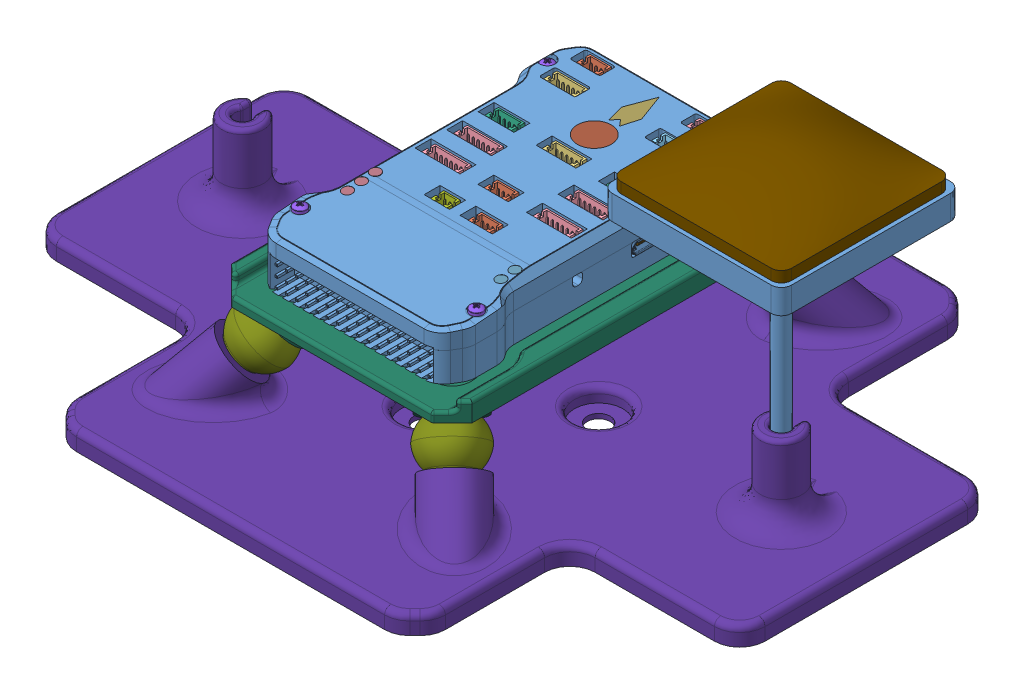
SolidWorks assembly S1000_Pixhawk, configuration Default. Lengths in mm.
Overall size (179 88.11 141.22).
35 component instances, 19 part files, 23 mates.
Components (placement in the parent):
- Pixhawk-1: Pixhawk [Défaut] at (-0.2703 0 -1.2478) x (-1 0 0) z (0 1 0) size (49.31 81.3 15.24)
  - Pixhawk APM-1: Pixhawk APM [Défaut] at (-24.9203 -39.4022 0) size (49.31 81.3 15.03)
  - DF13-3P-1.25DSA-1: DF13-3P-1.25DSA [Défaut] at (0.001 -60.127 12.2305) x (0 -1 0) z (-1 0 0) size (3.4 6.6 5.4)
  - DF13-5P-1.25DSA-1: DF13-5P-1.25DSA [Défaut] at (0.5502 -52.3839 12.2305) x (0 -1 0) z (-1 0 0) size (3.4 6.6 7.9)
  - DF13-6P-1.25DSA-1: DF13-6P-1.25DSA [Défaut] at (-27.5951 -60.0382 12.2305) x (0 -1 0) z (-1 0 0) size (3.4 6.6 9.15)
  - DF13-7P-1.25DSA-1: DF13-7P-1.25DSA [Défaut] at (-26.4213 -52.538 12.2305) x (0 -1 0) z (-1 0 0) size (3.4 6.6 10.4)
  - DF13-4P-1.25DSA-1: DF13-4P-1.25DSA [Défaut] at (-0.0265 -37.0823 12.2305) x (0 -1 0) z (-1 0 0) size (3.4 6.6 6.65)
  - DF13-4P-1.25DSA-2: DF13-4P-1.25DSA [Défaut] at (-30.3382 -37.0823 12.2305) x (0 -1 0) z (-1 0 0) size (3.4 6.6 6.65)
  - DF13-5P-1.25DSA-2: DF13-5P-1.25DSA [Défaut] at (-14.4216 -37.0823 12.2305) x (0 -1 0) z (-1 0 0) size (3.4 6.6 7.9)
  - DF13-6P-1.25DSA-2: DF13-6P-1.25DSA [Défaut] at (-0.012 -29.2904 12.2305) x (0 -1 0) z (-1 0 0) size (3.4 6.6 9.15)
  - DF13-6P-1.25DSA-3: DF13-6P-1.25DSA [Défaut] at (-0.012 -21.2194 12.2305) x (0 -1 0) z (-1 0 0) size (3.4 6.6 9.15)
  - DF13-6P-1.25DSA-4: DF13-6P-1.25DSA [Défaut] at (-27.948 -29.2904 12.2305) x (0 -1 0) z (-1 0 0) size (3.4 6.6 9.15)
  - DF13-6P-1.25DSA-5: DF13-6P-1.25DSA [Défaut] at (-27.948 -21.2194 12.2305) x (0 -1 0) z (-1 0 0) size (3.4 6.6 9.15)
  - DF13-3P-1.25DSA-2: DF13-3P-1.25DSA [Défaut] at (-15.6441 -21.2194 12.2305) x (0 -1 0) z (-1 0 0) size (3.4 6.6 5.4)
  - DF13-2P-1.25DSA-1: DF13-2P-1.25DSA [Défaut] at (-11.2684 -12.1811 12.2305) x (0 -1 0) z (-1 0 0) size (3.4 6.6 4.15)
  - DF13-3P-1.25DSA-3: DF13-3P-1.25DSA [Défaut] at (-20.7011 -12.1811 12.2305) x (0 -1 0) z (-1 0 0) size (3.4 6.6 5.4)
  - pan head cross recess screw_iso-1: pan head cross recess screw_iso [ISO 7045 - M1.6 x 3 - Z --- 3N] at (21.8797 32.2978 14.8) x (0 0 -1) z (1 0 0) size (4.27 3.2 3.2)
  - pan head cross recess screw_iso-2: pan head cross recess screw_iso [ISO 7045 - M1.6 x 3 - Z --- 3N] at (-22.4203 32.2978 14.8) x (0 0 -1) z (1 0 0) size (4.27 3.2 3.2)
  - pan head cross recess screw_iso-3: pan head cross recess screw_iso [ISO 7045 - M1.6 x 3 - Z --- 3N] at (21.8797 -29.8022 14.8) x (0 0 -1) z (1 0 0) size (4.27 3.2 3.2)
  - pan head cross recess screw_iso-4: pan head cross recess screw_iso [ISO 7045 - M1.6 x 3 - Z --- 3N] at (-22.4203 -29.8022 14.8) x (0 0 -1) z (1 0 0) size (4.27 3.2 3.2)
  - micro USB-2: micro USB [Défaut] at (-38.5288 4.0262 13.8589) x (0 1 0) z (-1 0 0) size (7.99 2.94 5.43)
    - micro usb02-1: micro usb02 [Défaut] at (-14.4796 6.4719 -20.7085) size (6.9 2.16 4.2)
    - micro USB-1: micro USB [Défaut] at (-14.4796 6.4719 -16.0085) size (7.99 2.94 5.43)
  - pièce10^Pixhawk-1: pièce10^Pixhawk [Défaut] at (-24.9203 -39.4022 14.5) size (8.5 8.5 0.5) (virtual)
  - pièce11^Pixhawk-1: pièce11^Pixhawk [Défaut] at (-24.9203 -39.4022 14.5) size (5.12 11.31 0.5) (virtual)
  - Pièce12^Pixhawk-1: Pièce12^Pixhawk [Défaut] at (-24.9203 -37.8072 19.1403) x (1 0 0) z (0 0.083045 0.996546) size (2.5 9.53 0.5) (virtual)
  - Pièce13^Pixhawk-1: Pièce13^Pixhawk [Défaut] at (-24.9203 -37.8072 19.1403) x (1 0 0) z (0 0.083045 0.996546) size (2.5 6.02 0.5) (virtual)
- Omni-Mount Top^S1000_Pixhawk-1: Omni-Mount Top^S1000_Pixhawk [Default] at (-23.809 -2.3813 -43.0091) x (-1 0 0) z (0 1 0) size (61.17 93.17 14.35) (virtual)
- Zenumuse Dampening Ball-1: Zenumuse Dampening Ball [Default] at (23.4392 -10.7929 38.4617) x (0.853553 0.5 -0.146447) z (-0.146447 0.5 0.853553) size (14.75 16 14.75)
- Zenumuse Dampening Ball-2: Zenumuse Dampening Ball [Default] at (23.4392 -10.7929 -40.9573) x (0.755922 0.638071 -0.146447) z (0.422589 -0.304738 0.853553) size (14.75 16 14.75)
- Zenumuse Dampening Ball-3: Zenumuse Dampening Ball [Default] at (-23.9798 -10.7929 38.4617) x (0.853553 -0.304738 0.422589) z (-0.146447 0.638071 0.755922) size (14.75 16 14.75)
- Zenumuse Dampening Ball-4: Zenumuse Dampening Ball [Default] at (-23.9798 -10.7929 -40.9573) x (0.853553 -0.5 -0.146447) z (-0.146447 -0.5 0.853553) size (14.75 16 14.75)
- Omni-Mount Bottom^S1000_Pixhawk-2: Omni-Mount Bottom^S1000_Pixhawk [Default] at (0 -33.0004 0) x (1 0 0) z (0 1 0) size (177.8 141.22 23.81) (virtual)
- 3DR_GPS-1: 3DR_GPS [Default] at (67.7462 42.7113 0.1588) size (42.74 17.78 42.74)
- 3DR_GPS_Mast-1: 3DR_GPS_Mast [Default] at (67.5875 -22.8588 0) size (45.02 70.51 45.02)
Mates (geometry in assembly coordinates):
- Coincident1: coincident anti-aligned: plane of Pixhawk-1/Pixhawk APM-1 through (24.65 0 -40.65) normal (0 -1 0); plane of assembly through (0 0 0) normal (0 1 0)
- Coincident2: coincident anti-aligned: plane of Pixhawk-1/Pixhawk APM-1; plane of assembly through (0 0 0) normal (1 0 0)
- Coincident3: coincident anti-aligned: plane of Pixhawk-1/Pixhawk APM-1 through (24.65 0 0) normal (0 0 -1); plane of assembly through (0 0 0) normal (0 0 1)
- Coincident7: coincident anti-aligned: plane of Pixhawk-1/Pixhawk APM-1 through (24.65 0 -40.65) normal (0 -1 0); plane of Omni-Mount Top^S1000_Pixhawk-1 through (-23.809 0 -43.0091) normal (0 1 0)
- Coincident10: coincident anti-aligned: plane of Zenumuse Dampening Ball-1 through (25.2176 -3.0311 34.2201) normal (0.5 -0.707107 0.5); plane of Omni-Mount Top^S1000_Pixhawk-1 through (20.0792 -6.0411 35.1017) normal (-0.5 0.707107 -0.5)
- Concentric1: concentric aligned: cylinder of Omni-Mount Top^S1000_Pixhawk-1 through (-353533.0476 499993.586 -353518.0252) axis (0.5 -0.707107 0.5) radius 6.985; cylinder of Zenumuse Dampening Ball-1 through (27.4392 -16.4497 42.4617) axis (0.5 -0.707107 0.5) radius 6.02
- Coincident12: coincident aligned: plane of Pixhawk-1; plane of Omni-Mount Top^S1000_Pixhawk-1
- Coincident17: coincident aligned: plane of Pixhawk-1; plane of Omni-Mount Top^S1000_Pixhawk-1
- Coincident18: coincident anti-aligned: plane of Omni-Mount Top^S1000_Pixhawk-1 through (-20.6198 -6.0411 -37.5973) normal (0.5 0.707107 0.5); plane of Zenumuse Dampening Ball-4 through (-15.4814 -9.0511 -38.4789) normal (-0.5 -0.707107 -0.5)
- Concentric2: concentric aligned: cylinder of Omni-Mount Top^S1000_Pixhawk-1 through (15.6361 45.2324 -1.3415) axis (-0.5 -0.707107 -0.5) radius 6.02; circle of Zenumuse Dampening Ball-4
- Concentric3: concentric aligned: cylinder of Omni-Mount Top^S1000_Pixhawk-1 through (15.6361 45.2324 -1.1542) axis (-0.5 -0.707107 0.5) radius 6.02; cylinder of Zenumuse Dampening Ball-3 through (-27.9798 -16.4497 42.4617) axis (-0.5 -0.707107 0.5) radius 6.02
- Coincident20: coincident anti-aligned: plane of Omni-Mount Top^S1000_Pixhawk-1 through (-20.6198 -6.0411 35.1017) normal (0.5 0.707107 -0.5); plane of Zenumuse Dampening Ball-3 through (-15.4814 -7.8756 37.6457) normal (-0.5 -0.707107 0.5)
- Concentric4: concentric aligned: cylinder of Omni-Mount Top^S1000_Pixhawk-1 through (-16.1766 45.2324 -1.3415) axis (0.5 -0.707107 -0.5) radius 6.02; cylinder of Zenumuse Dampening Ball-2 through (27.4392 -16.4497 -44.9573) axis (0.5 -0.707107 -0.5) radius 6.02
- Coincident21: coincident anti-aligned: plane of Omni-Mount Top^S1000_Pixhawk-1 through (20.0792 -6.0411 -37.5973) normal (-0.5 0.707107 0.5); plane of Zenumuse Dampening Ball-2 through (24.6299 -2.1999 -38.4789) normal (0.5 -0.707107 -0.5)
- Coincident26: coincident aligned: plane of Omni-Mount Bottom^S1000_Pixhawk-2; plane of assembly through (0 0 0) normal (1 0 0)
- Concentric6: concentric anti-aligned: cylinder of Zenumuse Dampening Ball-3 through (-27.9798 -16.4497 42.4617) axis (-0.5 -0.707107 0.5) radius 6.02; cylinder of Omni-Mount Bottom^S1000_Pixhawk-2 through (-44.4787 -39.7827 58.9606) axis (0.5 0.707107 -0.5) radius 6.02
- Coincident27: coincident anti-aligned: plane of Omni-Mount Bottom^S1000_Pixhawk-2 through (0 -33.0004 0) normal (0 0 -1); plane of assembly through (0 0 0) normal (0 0 1)
- Coincident28: coincident anti-aligned: plane of 3DR_GPS-1 through (67.7462 42.7113 0.1588) normal (0 -1 0); plane of 3DR_GPS_Mast-1 through (67.5875 42.7113 0) normal (0 1 0)
- Coincident29: coincident anti-aligned: plane of 3DR_GPS-1 through (46.3785 50.3313 21.5265) normal (-1 0 0); plane of 3DR_GPS_Mast-1 through (46.3785 47.6516 0) normal (1 0 0)
- Coincident30: coincident anti-aligned: plane of 3DR_GPS-1 through (46.3785 50.3313 -21.209) normal (0 0 -1); plane of 3DR_GPS_Mast-1 through (67.5875 47.6516 -21.209) normal (0 0 1)
- Concentric8: concentric aligned: cylinder of Omni-Mount Bottom^S1000_Pixhawk-2 through (67.5875 -3.8088 0) axis (0 -1 0) radius 2.05; cylinder of 3DR_GPS_Mast-1 through (67.5875 40.0316 0) axis (0 -1 0) radius 1.9939
- Coincident31: coincident anti-aligned: plane of Omni-Mount Bottom^S1000_Pixhawk-2 through (0 -22.8588 0) normal (0 1 0); plane of 3DR_GPS_Mast-1 through (67.5875 -22.8588 0) normal (0 -1 0)
- Parallel1: parallel anti-aligned: plane of Omni-Mount Top^S1000_Pixhawk-1 through (29.9347 2.3813 -43.0091) normal (1 0 0); plane of 3DR_GPS_Mast-1 through (45.0767 47.6516 0) normal (-1 0 0)
